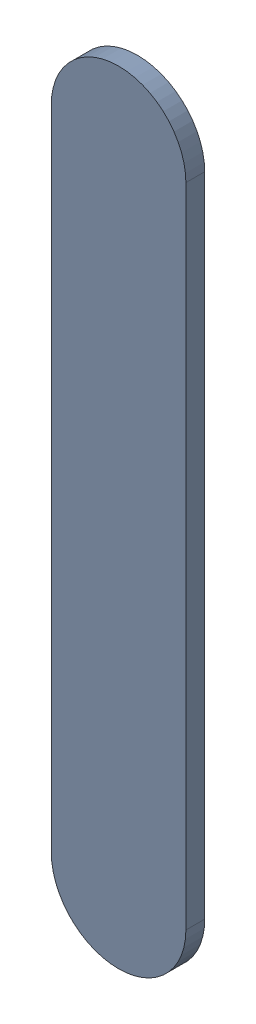
SolidWorks assembly Track (27.19mm,44.778mm)(27.19mm,46mm) on Top Layer, configuration Predeterminado. Lengths in mm.
Overall size (0.25 1.48 0.04).
2 component instances, 1 part files, 0 mates.
Components (placement in the parent):
- Track (27.19mm,44.778mm)(27.19mm,46mm) on Top Layer-1-1: Track (27.19mm,44.778mm)(27.19mm,46mm) on Top Layer-1 [Predeterminado] at (-68.317 -44.187 -0.0457) size (0.25 1.48 0.04)
  - Track (27.19mm,44.778mm)(27.19mm,46mm) on Top Layer-Part-1-1: Track (27.19mm,44.778mm)(27.19mm,46mm) on Top Layer-Part-1 [Predeterminado] at origin size (0.25 1.48 0.04)
